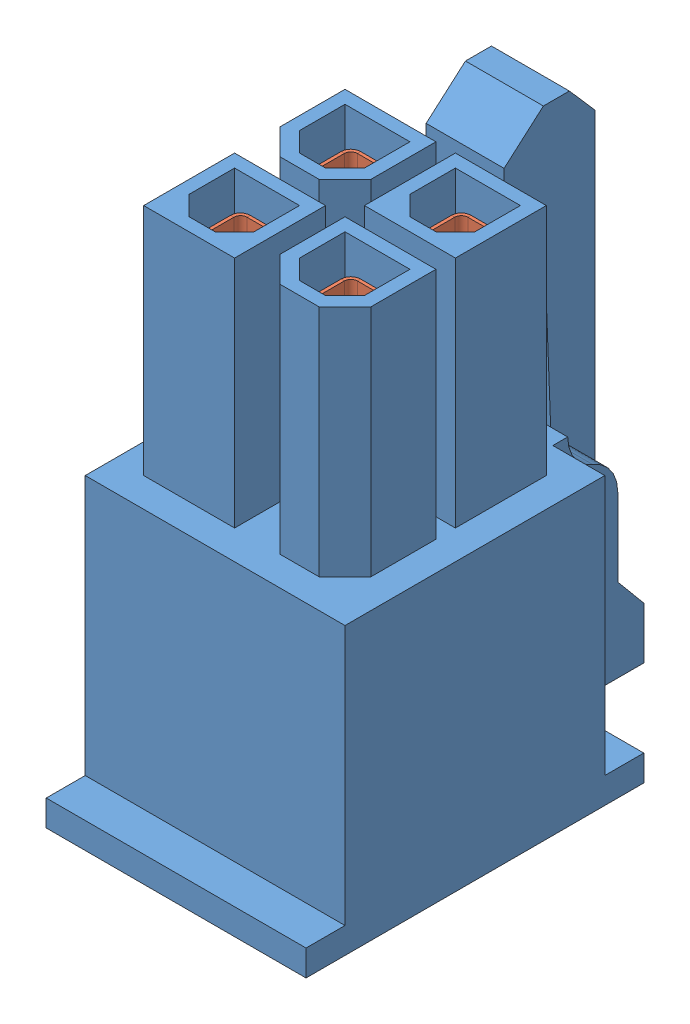
SolidWorks assembly ATX-12V-4-Pin, configuration Default. Lengths in mm.
Overall size (10 21 15).
5 component instances, 2 part files, 0 mates.
Components (placement in the parent):
- ATX-12V-4-Pin-Body-1: ATX-12V-4-Pin-Body [Default] at (0.2041 -8.9156 21) size (10 21 15)
- ATX-Main-24-Pin-crimp-1: ATX-Main-24-Pin-crimp [Default] at (2.3291 0.8097 24.15) x (0 1 0) z (-1 0 0) size (15.03 2.9 3.08)
- ATX-Main-24-Pin-crimp-2: ATX-Main-24-Pin-crimp [Default] at (2.3291 0.8097 19.9) x (0 1 0) z (-1 0 0) size (15.03 2.9 3.08)
- ATX-Main-24-Pin-crimp-3: ATX-Main-24-Pin-crimp [Default] at (-1.9209 0.8097 19.9) x (0 1 0) z (-1 0 0) size (15.03 2.9 3.08)
- ATX-Main-24-Pin-crimp-4: ATX-Main-24-Pin-crimp [Default] at (-1.9209 0.8097 24.15) x (0 1 0) z (-1 0 0) size (15.03 2.9 3.08)
